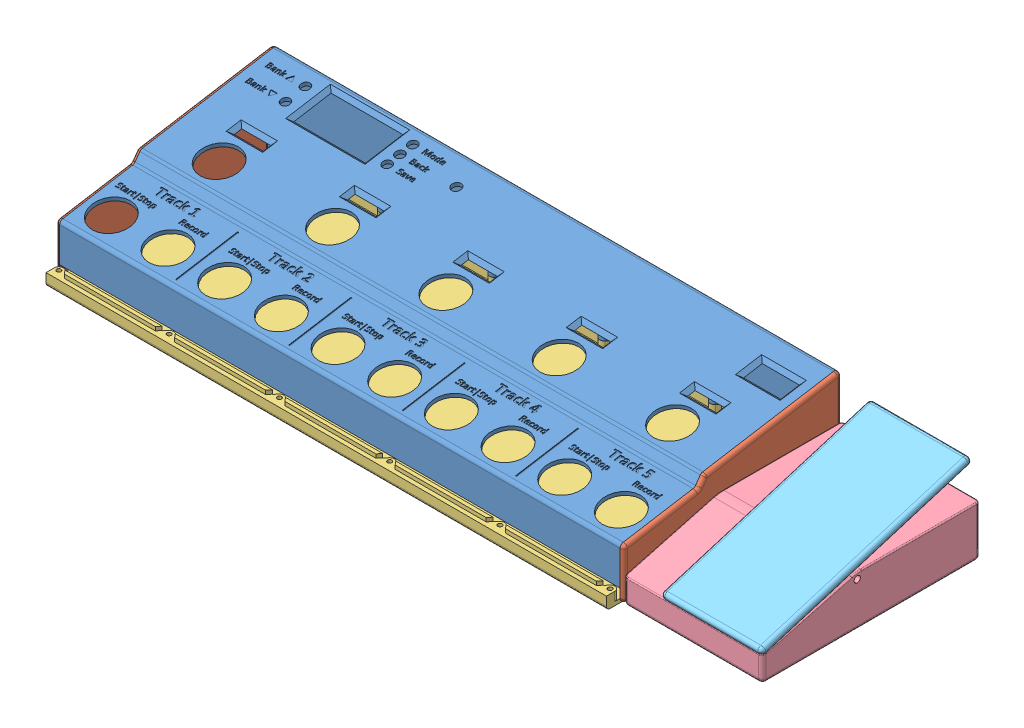
SolidWorks assembly Footpedal, configuration Default. Lengths in mm.
Overall size (561 74.98 183.81).
8 component instances, 6 part files, 15 mates.
Components (placement in the parent):
- Top_Shell-1: Top_Shell [Default] at (-329.9746 -15.2195 53.828) size (445 64.46 172.95)
- Diffusor_Test3-1: Diffusor_Test3 [Default] at (-309.9746 26.2117 119.7787) x (1 0 0) z (0 -0.986631 -0.16297) size (30 30 13.55) (hidden)
- SidePlate-2: SidePlate [Left] at origin size (5 74.46 172.95)
- Base2-1: Base2 [Default] at origin size (445 13 183.81)
- SidePlate-3: SidePlate [Right] at (441 0 0) size (5 74.46 172.95)
- effectPedal-1: effectPedal [Default] at (118.0415 -12.4245 -43.9145) x (0 0 -1) z (1 0 0) size (174.18 74.98 110)
  - effectPedal_Bottom-1: effectPedal_Bottom [Default] at (-43.9145 12.4245 -0.0161) size (172.95 40 110)
  - effectPedal_Top-1: effectPedal_Top [Default] at (-110.9629 33.9004 29.9839) x (0.956474 0.291818 0) z (0 0 1) size (174 16.5 80)
Mates (geometry in assembly coordinates):
- Concentric1: concentric: cylinder of assembly; cylinder of assembly; cylinder of Top_Shell-1 through (-309.9746 13.3855 117.6601) axis (0 0.986631 0.16297) radius 15.3; cylinder of Diffusor_Test3-1 through (-309.9746 26.2117 119.7787) axis (0 0.986631 0.16297) radius 15
- Parallel2: parallel: plane of assembly through (0 0 0) normal (1 0 0); plane of Diffusor_Test3-1 through (-317.0746 23.077 123.4156) normal (1 0 0); plane of assembly
- Coincident4: coincident: plane of Top_Shell-1 through (75.0254 -15.2195 53.828) normal (1 0 0); plane of ? through (75.0254 0 0) normal (-1 0 0)
- Coincident5: coincident: line of Top_Shell-1 through (75.0254 17.2354 140.305) axis (0 -1 0); line of ? through (75.0254 -19.5021 140.305) axis (0 1 0)
- Coincident6: coincident: line of Top_Shell-1 through (75.0254 29.3562 82.3332) axis (0 -0.16297 0.986631); line of ? through (75.0254 20.1953 137.7939) axis (0 0.16297 -0.986631)
- Coincident7: coincident: plane of assembly; plane of assembly; plane of Top_Shell-1 through (115.0254 -15.2195 53.828) normal (1 0 0); plane of SidePlate-3 through (115.0254 0 0) normal (-1 0 0)
- Coincident8: coincident: line of assembly; line of assembly; line of Top_Shell-1 through (115.0254 17.2354 140.305) axis (0 -1 0); line of SidePlate-3 through (115.0254 -17.2195 140.305) axis (0 1 0)
- Coincident9: coincident: line of assembly; line of assembly; line of Top_Shell-1 through (115.0254 29.3562 82.3332) axis (0 -0.16297 0.986631); line of SidePlate-3 through (115.0254 20.1953 137.7939) axis (0 0.16297 -0.986631)
- InPlace1: in place: plane of SidePlate-3 through (118.0254 0 0) normal (1 0 0); plane of effectPedal-1/effectPedal_Bottom-1 through (118.0254 0 0) normal (1 0 0); moOrthogonalPlaneRef_w of SidePlate-3 through (118.0254 0 0) normal (1 0 0); plane of effectPedal-1/effectPedal_Bottom-1 through (118.0254 0 0) normal (0 1 0); plane of SidePlate-3 through (118.0254 0 0) normal (1 0 0); plane of effectPedal-1/effectPedal_Bottom-1 through (118.0254 0 0) normal (0 0 -1); plane of SidePlate-3 through (118.0254 0 0) normal (1 0 0); unknown of effectPedal-1/effectPedal_Bottom-1
- Coincident10: coincident: plane of assembly; plane of assembly; plane of SidePlate-3; plane of ?
- Coincident11: coincident: plane of SidePlate-3 through (118.0254 0 0) normal (0 1 0); plane of effectPedal-1/effectPedal_Bottom-1 through (118.0254 0 0) normal (0 1 0)
- Coincident12: coincident: plane of SidePlate-3 through (118.0254 0 0) normal (0 0 1); plane of effectPedal-1/effectPedal_Bottom-1 through (118.0254 0 0) normal (0 0 -1)
- Coincident13: coincident: plane of SidePlate-3 through (118.0254 0 0) normal (1 0 0); plane of effectPedal-1/effectPedal_Bottom-1 through (118.0254 0 0) normal (-1 0 0)
- Coincident14: coincident: plane of Top_Shell-1 through (115.0254 54.7805 -32.649) normal (0 0 -1); plane of effectPedal-1/effectPedal_Bottom-1 through (228.0254 -20.2195 -32.649) normal (0 0 -1)
- Coincident16: coincident: plane of ? through (115.0254 -20.2195 -32.649) normal (0 -1 0); plane of effectPedal-1/effectPedal_Bottom-1 through (228.0254 -20.2195 140.305) normal (0 -1 0)
